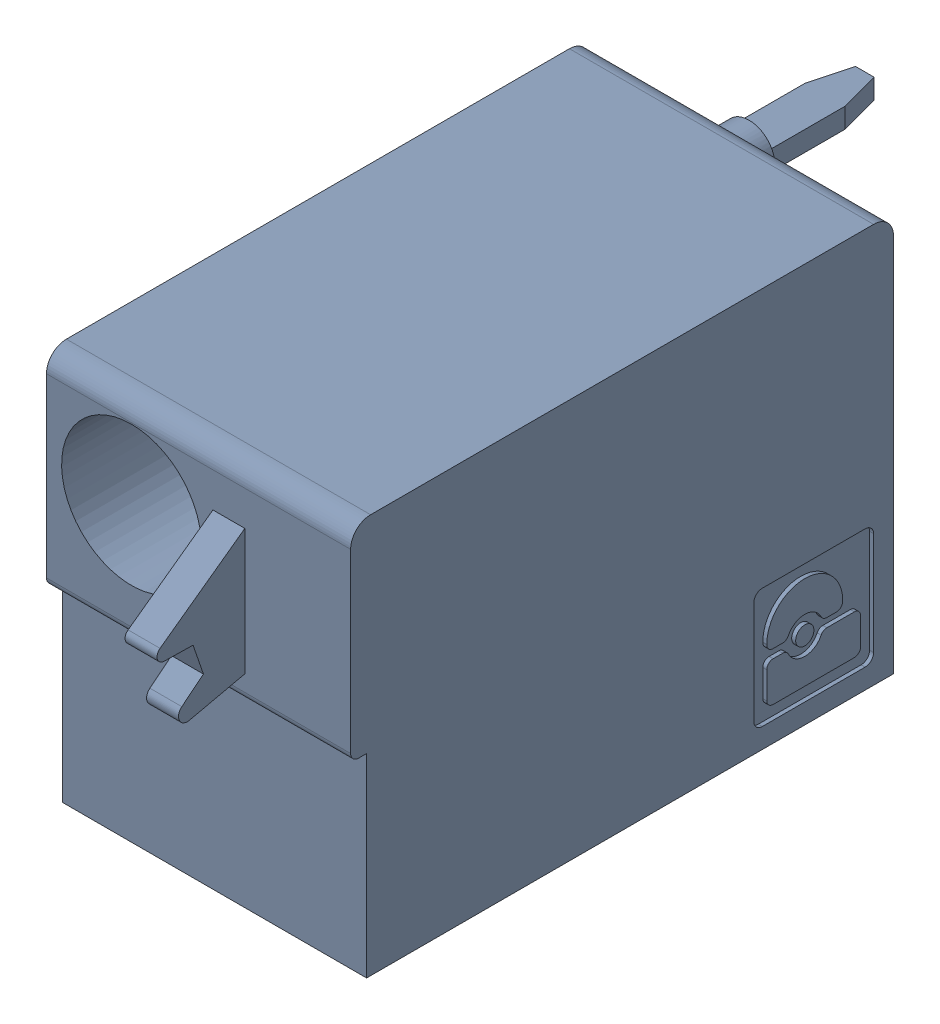
SolidWorks assembly J91, configuration Default. Lengths in mm.
Overall size (7.62 10 19.2).
2 component instances, 1 part files, 0 mates.
Components (placement in the parent):
- 1790487-1: 1790487 [Default] at (254.405 -15.67 -10.6) x (0 1 0) z (1 0 0) size (10 19.2 7.62)
  - ffkdsa1-v2-7.62-1: ffkdsa1-v2-7.62 [Default] at (-15.6914 -27.508 9.12) x (0 -1 0) z (0 0 1) size (19.2 10 7.62)
